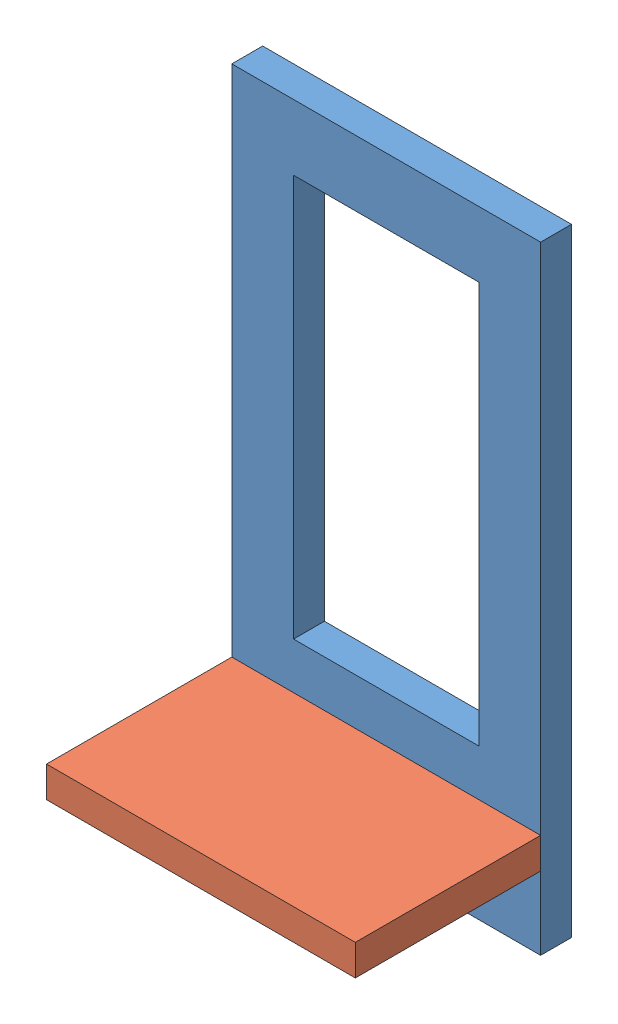
SolidWorks assembly Assem1, configuration Default. Lengths in mm.
Overall size (50 100 35).
2 component instances, 2 part files, 3 mates.
Components (placement in the parent):
- solarSupport-1: solarSupport [Default] at (-11.6853 110.7082 41.6485) x (0 0 -1) z (0 -1 0) size (5 50 100)
- sideServoHolder-2: sideServoHolder [Default] at (38.3147 22.5342 71.6485) size (50 5 35)
Mates (geometry in assembly coordinates):
- Coincident1: coincident: plane of assembly; plane of assembly; plane of solarSupport-1 through (8.3147 22.5342 36.6485) normal (0 1 0); plane of sideServoHolder-2 through (38.3147 22.5342 71.6485) normal (0 -1 0)
- Coincident3: coincident: plane of assembly; plane of assembly; plane of solarSupport-1 through (-1.6853 22.5342 36.6485) normal (1 0 0); plane of sideServoHolder-2 through (-1.6853 27.5342 41.6485) normal (-1 0 0)
- Coincident4: coincident: plane of assembly; plane of assembly; plane of solarSupport-1 through (-11.6853 110.7082 36.6485) normal (0 0 -1); plane of sideServoHolder-2 through (8.3147 27.5342 36.6485) normal (0 0 -1)
